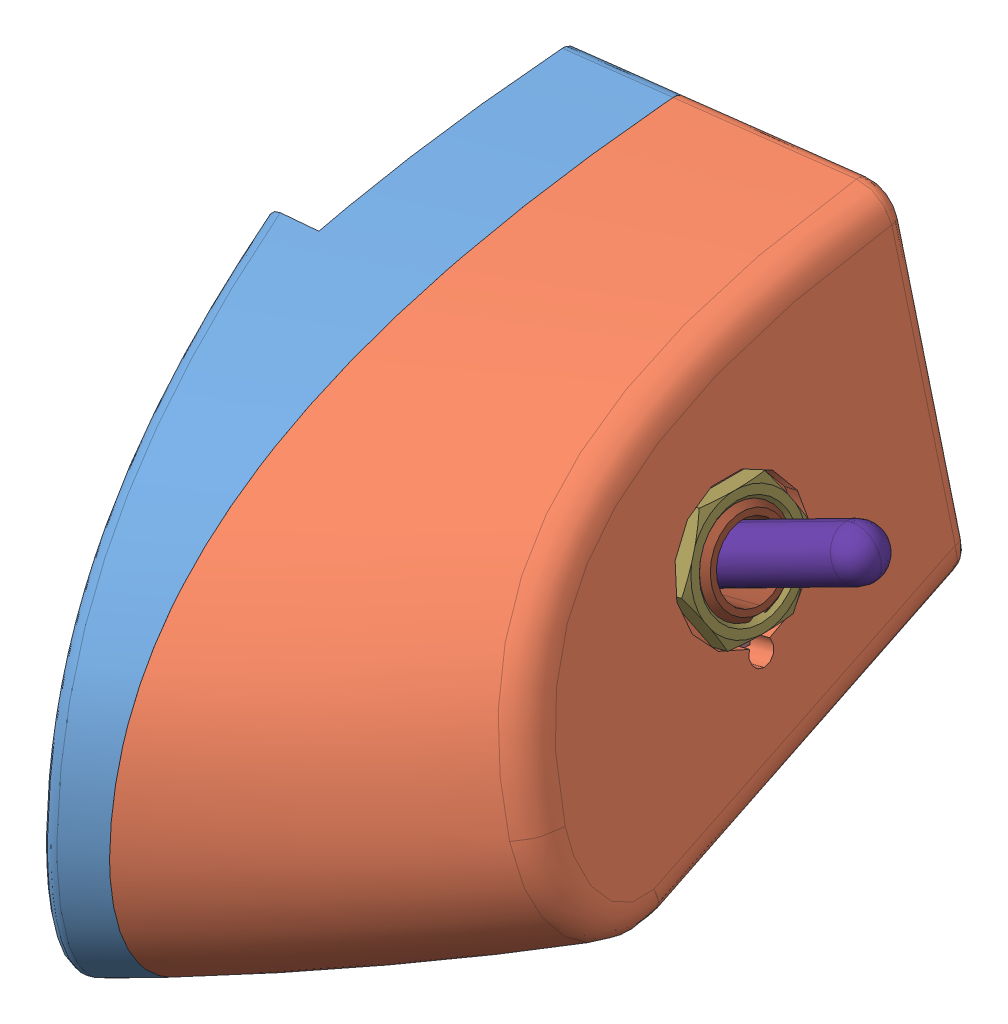
SolidWorks assembly Outboard Throttle Grip, configuration Default. Lengths in mm.
Overall size (73.43 74.91 87.55).
25 component instances, 17 part files, 34 mates.
Components (placement in the parent):
- Right Outboard Throttle Grip Housing-1: Right Outboard Throttle Grip Housing [Default] at origin size (26.95 74.91 87.55)
- Left Outboard Throttle Grip Housing-1: Left Outboard Throttle Grip Housing [Default] at origin size (43.51 72.27 85.49)
- P3-11122-1: P3-11122 [Default] at (22.2251 5.9653 48.09) x (-0.945358 -0.295929 0.136837) z (0.225703 -0.291136 0.929676) size (15.82 34.01 15.82)
- P3-11122-2: P3-11122 [Default] at (41.7267 12.9829 42.839) x (-0.945358 -0.295929 0.136837) z (0.225703 -0.291136 0.929676) size (15.82 34.01 15.82)
- 93365A140 - INSERT, 8-32, BRASS, FOR PLASTICS-1: 93365A140 - INSERT, 8-32, BRASS, FOR PLASTICS [93365A140] at (9.525 28.702 22.098) x (0 1 0) z (0 0 1) size (6.35 5.19 6.35)
- 93365A140 - INSERT, 8-32, BRASS, FOR PLASTICS-2: 93365A140 - INSERT, 8-32, BRASS, FOR PLASTICS [93365A140] at (9.525 9.652 9.398) x (0 1 0) z (0 0 1) size (6.35 5.19 6.35)
- 93365A140 - INSERT, 8-32, BRASS, FOR PLASTICS-3: 93365A140 - INSERT, 8-32, BRASS, FOR PLASTICS [93365A140] at (23.198 36.6475 6.35) x (0 1 0) z (0 0 1) size (6.35 5.19 6.35)
- 93365A140 - INSERT, 8-32, BRASS, FOR PLASTICS-4: 93365A140 - INSERT, 8-32, BRASS, FOR PLASTICS [93365A140] at (23.198 6.35 25.4) x (0 1 0) z (0 0 1) size (6.35 5.19 6.35)
- 93365A140 - INSERT, 8-32, BRASS, FOR PLASTICS-5: 93365A140 - INSERT, 8-32, BRASS, FOR PLASTICS [93365A140] at (23.198 17.5975 57.15) x (0 1 0) z (0 0 1) size (6.35 5.19 6.35)
- 98381A471 - PIN, DOWEL, .125 X .500, ALLOY STEEL-1: 98381A471 - PIN, DOWEL, .125 X .500, ALLOY STEEL [98381A471] at (23.198 -10.9775 63.5) size (12.7 3.17 3.17)
- 91249A197 - PHS, 8-32 x .750, 18-8, BLACK-OXIDE-1: 91249A197 - PHS, 8-32 x .750, 18-8, BLACK-OXIDE [91249A197] at (34.036 36.6475 6.35) x (0 0.936287 0.351235) z (-1 0 0) size (8.18 8.18 22.03)
- 91249A197 - PHS, 8-32 x .750, 18-8, BLACK-OXIDE-3: 91249A197 - PHS, 8-32 x .750, 18-8, BLACK-OXIDE [91249A197] at (34.036 6.35 25.4) x (0 0.868755 0.495243) z (-1 0 0) size (8.18 8.18 22.03)
- 91249A197 - PHS, 8-32 x .750, 18-8, BLACK-OXIDE-5: 91249A197 - PHS, 8-32 x .750, 18-8, BLACK-OXIDE [91249A197] at (34.036 17.5975 57.15) x (0 0.798623 0.601832) z (-1 0 0) size (8.18 8.18 22.03)
- 93365A120_BRASS HEAT-SET INSERT FOR PLASTICS_4-40-1: 93365A120_BRASS HEAT-SET INSERT FOR PLASTICS_4-40 [93365A120] at (36.8165 -9.2433 38.4278) x (-0.683112 -0.40511 0.607655) z (0.691377 -0.090669 0.716783) size (4.37 3.82 4.37)
- 90272A106 - PHS, 4-40 x .250, STEEL, ZINC-1: 90272A106 - PHS, 4-40 x .250, STEEL, ZINC [90272A106] at (35.4898 -4.1134 40.3564) x (-0.207842 -0.390854 0.89668) z (0.23528 -0.909761 -0.34202) size (5.56 5.56 8.42)
- 90618A200 - WASHER, #4 X .250, 18-8, BLACK OXIDE, MS15795-803B-1: 90618A200 - WASHER, #4 X .250, 18-8, BLACK OXIDE, MS15795-803B [90618A200] at (36.9839 -9.8904 38.1845) x (0.971541 0.210217 0.109166) z (-0.027416 -0.357971 0.93333) size (6.35 0.71 6.35)
- M2011B2B1W01-1: M2011B2B1W01 [Default] at (44.9176 20.4163 25.4) x (0 0 1) z (-0.25038 0.968148 0) size (18.21 44.24 19.49)
  - _M20112B2B1W01_switch_2-1: _M20112B2B1W01_switch_2 [Default] at origin size (7.9 9.17 13)
  - _M201B1M201_bushing_4-1: _M201B1M201_bushing_4 [Default] at (0 -0.254 0) size (12 19.04 13)
  - _AT503M_6-1: _AT503M_6 [Default] at (0 10.5308 0) x (1 0 0) z (0 1 0) size (16.01 15.91 2.39)
  - _AT506M_8-1: _AT506M_8 [Default] at (0 5.1714 0) x (0 0 1) z (0 1 0) size (18.62 18.21 2.79)
  - _AT508_10-1: _AT508_10 [Default] at (0 4.9174 0) x (1 0 0) z (0 -1 0) size (15.8 15.8 0.51)
  - _AT527M_12-1: _AT527M_12 [Default] at (0 3.6601 0) x (0.993403 0 -0.114675) z (0 -1 0) size (16.01 17.77 2.01)
  - _M201101_terminals_14-1: _M201101_terminals_14 [Default] at (0 -9.4234 0) size (6.38 5 12.5)
  - _M20B2_toggles_16-1: _M20B2_toggles_16 [Default] at (0 11.9888 0) x (0 0 -1) z (1 0 0) size (11.39 26.26 5.99)
Mates (geometry in assembly coordinates):
- Coincident1: coincident: plane of ? through (22.3395 0 90.2295) normal (-0.951057 0 0.309017); plane of ? through (22.3395 0 90.2295) normal (-0.951057 0 0.309017)
- Coincident2: coincident: plane of ? through (3.175 0 0) normal (0 1 0); plane of ? through (3.175 0 0) normal (0 1 0)
- Coincident3: coincident aligned: plane of ? through (6.35 21.5647 31.75) normal (0 0 -1); plane of ? through (6.35 21.5647 31.75) normal (0 0 -1)
- Concentric1: concentric aligned: cylinder of Right Outboard Throttle Grip Housing-1 through (27.0657 -12.7521 41.0533) axis (-0.23528 0.909761 0.34202) radius 8.128; cylinder of P3-11122-1 through (27.6947 -15.1842 40.139) axis (-0.23528 0.909761 0.34202) radius 7.9121
- Coincident5: coincident anti-aligned: plane of Right Outboard Throttle Grip Housing-1 through (25.5717 -6.9751 43.2251) normal (0.23528 -0.909761 -0.34202); plane of P3-11122-1 through (25.5717 -6.9751 43.2251) normal (-0.23528 0.909761 0.34202)
- Concentric2: concentric aligned: cylinder of Left Outboard Throttle Grip Housing-1 through (46.5673 -5.7346 35.8023) axis (-0.23528 0.909761 0.34202) radius 8.128; cylinder of P3-11122-2 through (47.1963 -8.1667 34.8879) axis (-0.23528 0.909761 0.34202) radius 7.9121
- Coincident6: coincident aligned: plane of P3-11122-1 through (27.0657 -12.7521 41.0533) normal (0.23528 -0.909761 -0.34202); plane of P3-11122-2 through (46.5673 -5.7346 35.8023) normal (0.23528 -0.909761 -0.34202)
- Concentric3: concentric anti-aligned: cone of Right Outboard Throttle Grip Housing-1 through (9.525 28.702 22.098) axis (1 0 0); cylinder of 93365A140 - INSERT, 8-32, BRASS, FOR PLASTICS-1 through (9.525 28.702 22.098) axis (-1 0 0) radius 2.8702
- Coincident7: coincident aligned: plane of Right Outboard Throttle Grip Housing-1 through (9.525 0 0) normal (-1 0 0); plane of 93365A140 - INSERT, 8-32, BRASS, FOR PLASTICS-1 through (9.525 28.702 22.098) normal (-1 0 0)
- Concentric4: concentric anti-aligned: cone of Right Outboard Throttle Grip Housing-1 through (9.525 9.652 9.398) axis (1 0 0); cylinder of 93365A140 - INSERT, 8-32, BRASS, FOR PLASTICS-2 through (9.525 9.652 9.398) axis (-1 0 0) radius 2.8702
- Coincident8: coincident aligned: plane of Right Outboard Throttle Grip Housing-1 through (9.525 0 0) normal (-1 0 0); plane of 93365A140 - INSERT, 8-32, BRASS, FOR PLASTICS-2 through (9.525 9.652 9.398) normal (-1 0 0)
- Concentric5: concentric anti-aligned: cone of Left Outboard Throttle Grip Housing-1 through (23.198 36.6475 6.35) axis (1 0 0); cylinder of 93365A140 - INSERT, 8-32, BRASS, FOR PLASTICS-3 through (23.198 36.6475 6.35) axis (-1 0 0) radius 2.8702
- Coincident9: coincident aligned: plane of Left Outboard Throttle Grip Housing-1 through (23.198 0 0) normal (-1 0 0); plane of 93365A140 - INSERT, 8-32, BRASS, FOR PLASTICS-3 through (23.198 36.6475 6.35) normal (-1 0 0)
- Concentric6: concentric anti-aligned: cone of Left Outboard Throttle Grip Housing-1 through (23.198 6.35 25.4) axis (1 0 0); cylinder of 93365A140 - INSERT, 8-32, BRASS, FOR PLASTICS-4 through (23.198 6.35 25.4) axis (-1 0 0) radius 2.8702
- Coincident10: coincident aligned: plane of Left Outboard Throttle Grip Housing-1 through (23.198 0 0) normal (-1 0 0); plane of 93365A140 - INSERT, 8-32, BRASS, FOR PLASTICS-4 through (23.198 6.35 25.4) normal (-1 0 0)
- Concentric7: concentric anti-aligned: cone of Left Outboard Throttle Grip Housing-1 through (23.198 17.5975 57.15) axis (1 0 0); cylinder of 93365A140 - INSERT, 8-32, BRASS, FOR PLASTICS-5 through (23.198 17.5975 57.15) axis (-1 0 0) radius 2.8702
- Coincident11: coincident aligned: plane of Left Outboard Throttle Grip Housing-1 through (23.198 0 0) normal (-1 0 0); plane of 93365A140 - INSERT, 8-32, BRASS, FOR PLASTICS-5 through (23.198 17.5975 57.15) normal (-1 0 0)
- Concentric8: concentric anti-aligned: cylinder of Left Outboard Throttle Grip Housing-1 through (23.198 -10.9775 63.5) axis (-1 0 0) radius 1.651; cylinder of 98381A471 - PIN, DOWEL, .125 X .500, ALLOY STEEL-1 through (16.848 -10.9775 63.5) axis (1 0 0) radius 1.5875
- Distance1: distance = 6.35 mm aligned: plane of 98381A471 - PIN, DOWEL, .125 X .500, ALLOY STEEL-1 through (16.848 -10.9775 63.5) normal (-1 0 0); plane of Left Outboard Throttle Grip Housing-1 through (23.198 0 0) normal (-1 0 0)
- Concentric9: concentric anti-aligned: cylinder of Right Outboard Throttle Grip Housing-1 through (9.525 36.6475 6.35) axis (-1 0 0) radius 4.5644; cylinder of 91249A197 - PHS, 8-32 x .750, 18-8, BLACK-OXIDE-1 through (34.036 36.6475 6.35) axis (1 0 0) radius 4.0894
- Coincident12: coincident anti-aligned: plane of Right Outboard Throttle Grip Housing-1 through (14.986 39.1049 6.35) normal (-1 0 0); plane of 91249A197 - PHS, 8-32 x .750, 18-8, BLACK-OXIDE-1 through (14.986 36.6475 6.35) normal (1 0 0)
- Concentric10: concentric anti-aligned: cylinder of Right Outboard Throttle Grip Housing-1 through (9.525 6.35 25.4) axis (-1 0 0) radius 4.5644; cylinder of 91249A197 - PHS, 8-32 x .750, 18-8, BLACK-OXIDE-3 through (34.036 6.35 25.4) axis (1 0 0) radius 4.0894
- Coincident13: coincident anti-aligned: plane of Right Outboard Throttle Grip Housing-1 through (14.986 8.8074 25.4) normal (-1 0 0); plane of 91249A197 - PHS, 8-32 x .750, 18-8, BLACK-OXIDE-3 through (14.986 6.35 25.4) normal (1 0 0)
- Concentric11: concentric anti-aligned: cylinder of Right Outboard Throttle Grip Housing-1 through (9.525 17.5975 57.15) axis (-1 0 0) radius 4.5644; cylinder of 91249A197 - PHS, 8-32 x .750, 18-8, BLACK-OXIDE-5 through (34.036 17.5975 57.15) axis (1 0 0) radius 4.0894
- Coincident14: coincident anti-aligned: plane of Right Outboard Throttle Grip Housing-1 through (14.986 20.0549 57.15) normal (-1 0 0); plane of 91249A197 - PHS, 8-32 x .750, 18-8, BLACK-OXIDE-5 through (14.986 17.5975 57.15) normal (1 0 0)
- Concentric12: concentric: cylinder of ? through (36.8165 -9.2433 38.4278) axis (-0.23528 0.909761 0.34202) radius 37.0201; cylinder of 93365A120_BRASS HEAT-SET INSERT FOR PLASTICS_4-40-1 through (36.0098 -6.1238 39.6006) axis (0.23528 -0.909761 -0.34202) radius 1.9431
- Coincident15: coincident aligned: plane of Left Outboard Throttle Grip Housing-1 through (30.9245 -7.3017 29.21) normal (0.23528 -0.909761 -0.34202); plane of 93365A120_BRASS HEAT-SET INSERT FOR PLASTICS_4-40-1 through (36.8165 -9.2433 38.4278) normal (0.23528 -0.909761 -0.34202)
- Concentric13: concentric anti-aligned: circle of 93365A120_BRASS HEAT-SET INSERT FOR PLASTICS_4-40-1; cylinder of 90618A200 - WASHER, #4 X .250, 18-8, BLACK OXIDE, MS15795-803B-1 through (36.8165 -9.2433 38.4278) axis (0.23528 -0.909761 -0.34202) radius 3.175
- Coincident16: coincident anti-aligned: plane of 93365A120_BRASS HEAT-SET INSERT FOR PLASTICS_4-40-1 through (36.8165 -9.2433 38.4278) normal (0.23528 -0.909761 -0.34202); plane of 90618A200 - WASHER, #4 X .250, 18-8, BLACK OXIDE, MS15795-803B-1 through (36.8165 -9.2433 38.4278) normal (-0.23528 0.909761 0.34202)
- Concentric14: concentric anti-aligned: circle of 90272A106 - PHS, 4-40 x .250, STEEL, ZINC-1; circle of 90618A200 - WASHER, #4 X .250, 18-8, BLACK OXIDE, MS15795-803B-1
- Coincident17: coincident anti-aligned: plane of 90272A106 - PHS, 4-40 x .250, STEEL, ZINC-1 through (36.9839 -9.8904 38.1845) normal (-0.23528 0.909761 0.34202); plane of 90618A200 - WASHER, #4 X .250, 18-8, BLACK OXIDE, MS15795-803B-1 through (36.9839 -9.8904 38.1845) normal (0.23528 -0.909761 -0.34202)
- Concentric21: concentric aligned: cylinder of Left Outboard Throttle Grip Housing-1 through (53.9572 22.7541 25.4) axis (0.968148 0.25038 0) radius 8.255; cylinder of M2011B2B1W01-1/_M201B1M201_bushing_4-1 through (44.7947 20.3845 25.4) axis (0.968148 0.25038 0) radius 6
- Parallel7: parallel anti-aligned: plane of Left Outboard Throttle Grip Housing-1 through (6.35 21.5647 0) normal (0 0 -1); plane of M2011B2B1W01-1/_M201B1M201_bushing_4-1 through (36.4655 24.9468 29.3497) normal (0 0 1)
- Coincident25: coincident anti-aligned: plane of Left Outboard Throttle Grip Housing-1 through (53.9572 22.7541 25.4) normal (0.968148 0.25038 0); plane of M2011B2B1W01-1/_AT503M_6-1 through (56.0597 14.6244 25.4) normal (-0.968148 -0.25038 0)
